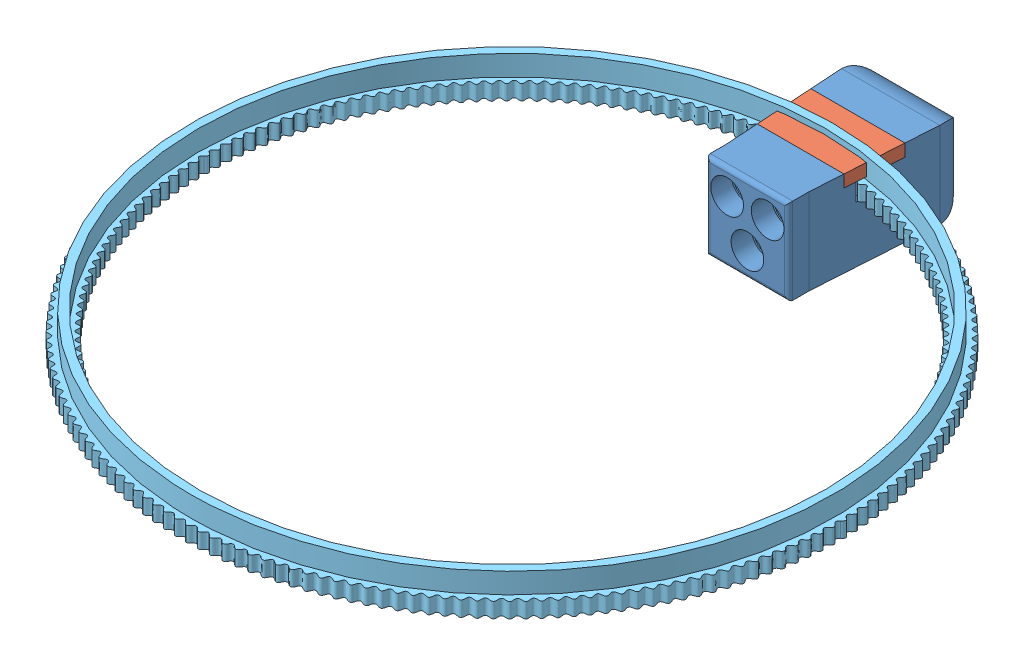
SolidWorks assembly whole-assembly, configuration Default. Lengths in mm.
Overall size (162.12 22.4 181.49).
6 component instances, 5 part files, 11 mates.
Components (placement in the parent):
- housing-1: housing [Default] at (17.411 11.8221 111.3683) size (24 21 43)
- lid-1: lid [Default] at (17.411 29.8221 111.3683) size (22.97 3 14)
- tooth-inside-1: tooth-inside [Default] at (17.3341 25.5221 111.3496) x (0.994214 0 -0.107421) z (0.107421 0 0.994214) size (5.39 4 5.76)
- tooth-outside-1: tooth-outside [Default] at (17.2899 25.5221 110.1839) x (0.998135 0 -0.061049) z (0.061049 0 0.998135) size (5.88 4 5.75)
- track-1: track [Default] at (17.411 25.5221 111.3683) x (0.999994 0 -0.003546) z (0.003546 0 0.999994) size (161.55 8.7 161.4)
- tooth-inside-2: tooth-inside [Default] at (17.3886 25.5221 112.6362) x (0.999793 0 0.020361) z (-0.020361 0 0.999793) size (5.39 4 5.76)
Mates (geometry in assembly coordinates):
- Coincident1: coincident anti-aligned: plane of housing-1 through (17.411 25.5221 111.3683) normal (0 1 0); plane of tooth-inside-1 through (64.368 25.5221 52.9254) normal (0 -1 0)
- Parallel1: parallel anti-aligned: plane of housing-1 through (10.4242 15.2199 45.7328) normal (0.997953 0 -0.063952); plane of tooth-inside-1 through (9.9779 168.1296 37.214) normal (-0.997953 0 0.063952)
- Coincident3: coincident anti-aligned: plane of housing-1 through (17.411 25.5221 111.3683) normal (0 1 0); plane of tooth-inside-2 through (71.4951 25.5221 60.6934) normal (0 -1 0)
- Parallel2: parallel anti-aligned: plane of housing-1 through (24.3978 15.2199 45.7328) normal (-0.997953 0 -0.063952); plane of tooth-inside-2 through (24.4568 162.7295 42.994) normal (0.997953 0 0.063952)
- Coincident6: coincident anti-aligned: plane of housing-1 through (17.411 25.5221 111.3683) normal (0 1 0); plane of tooth-outside-1 through (70.304 25.5221 50.267) normal (0 -1 0)
- Parallel3: parallel anti-aligned: plane of housing-1 through (14.411 15.5221 22.4239) normal (1 0 0); plane of tooth-outside-1 through (14.4805 184.8655 29.7336) normal (-1 0 0)
- Coincident16: coincident anti-aligned: plane of housing-1 through (17.411 29.8221 111.3683) normal (0 1 0); plane of lid-1 through (17.411 29.8221 111.3683) normal (0 -1 0)
- Coincident17: coincident anti-aligned: plane of housing-1 through (28.8984 29.8221 26.8683) normal (0 0 1); plane of lid-1 through (28.8984 29.8221 26.8683) normal (0 0 -1)
- Coincident19: coincident aligned: plane of housing-1 through (7.3335 32.8221 48.8683) normal (-0.997953 0 0.063952); plane of lid-1 through (7.3335 32.8221 48.8683) normal (-0.997953 0 0.063952)
- Coincident21: coincident anti-aligned: plane of housing-1 through (17.411 25.5221 111.3683) normal (0 1 0); plane of track-1 through (17.6916 25.5221 191.3662) normal (0 -1 0)
- Concentric1: concentric anti-aligned: circle of lid-1; circle of track-1
